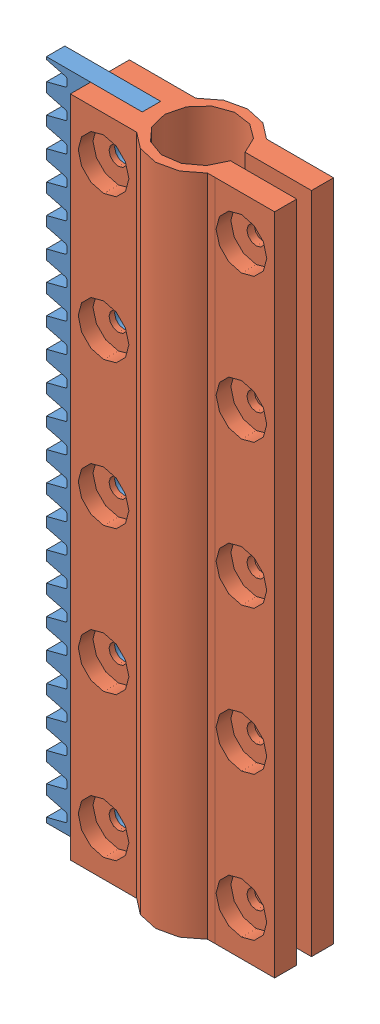
SolidWorks assembly rack assembly, configuration Default. Lengths in mm.
Overall size (42.8 114.3 15.88).
2 component instances, 2 part files, 2 mates.
Components (placement in the parent):
- rack laser-1: rack laser [57655K64] at (10.1208 166.8944 47.4677) x (0 1 0) z (0 0 1) size (114.3 16.51 3.17)
- rackcollar-1: rackcollar [Default] at (27.0148 14.4944 47.4677) size (35.18 114.3 15.88)
Mates (geometry in assembly coordinates):
- Coincident4: coincident: plane of rack laser-1 through (1.8658 319.2944 49.0552) normal (0 0 1); plane of rackcollar-1 through (18.3758 128.7944 49.0552) normal (0 0 -1)
- Coincident6: coincident: plane of rack laser-1 through (18.3758 14.4944 49.0552) normal (1 0 0); plane of rackcollar-1 through (18.3758 14.4944 47.4677) normal (-1 0 0)
